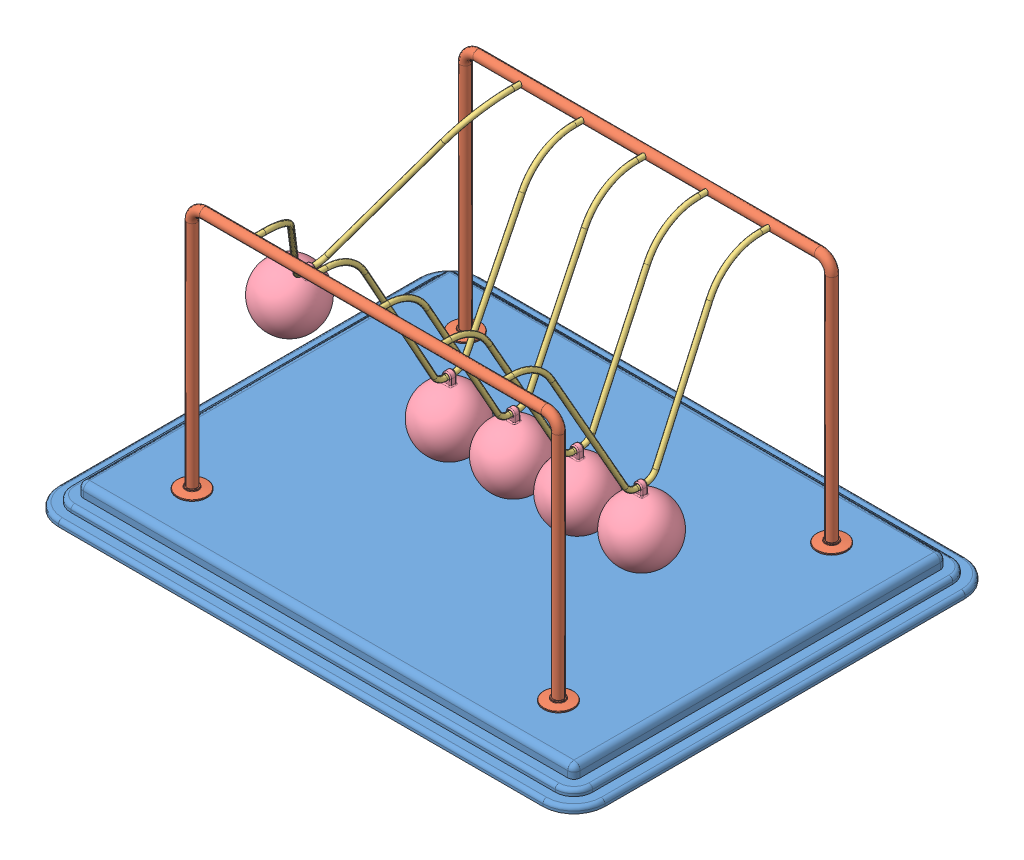
SolidWorks assembly Newtons Cradle NewtonsCradle 0242, configuration Default. Lengths in mm.
Overall size (440 222 340).
13 component instances, 4 part files, 34 mates.
Components (placement in the parent):
- Base NewtonsCradle 0242-1: Base NewtonsCradle 0242 [Default] at (-16.2968 -4.1587 11.425) size (440 20 340)
- frame NewtonsCradle 0242-1: frame NewtonsCradle 0242 [Default] at (-16.2968 144.4547 -98.575) size (319 202 24)
- frame NewtonsCradle 0242-2: frame NewtonsCradle 0242 [Default] at (-16.2968 144.4547 121.425) x (-1 0 0) z (0 0 -1) size (319 202 24)
- Hanging thing NewtonsCradle 0242-1: Hanging thing NewtonsCradle 0242 [Default] at (-157.6326 134.1825 11.425) x (0 0 1) z (-0.859985 0.510319 0) size (220 129 4)
- Hanging thing NewtonsCradle 0242-2: Hanging thing NewtonsCradle 0242 [Default] at (-66.576 122.8418 11.425) x (0 0 1) z (-0.999994 0.003446 0) size (220 129 4)
- Hanging thing NewtonsCradle 0242-3: Hanging thing NewtonsCradle 0242 [Default] at (-15.6923 122.8436 11.425) x (0 0 1) z (-0.999972 -0.007464 0) size (220 129 4)
- Hanging thing NewtonsCradle 0242-4: Hanging thing NewtonsCradle 0242 [Default] at (35.2213 122.8555 11.425) x (0 0 1) z (-0.999824 -0.018742 0) size (220 129 4)
- Hanging thing NewtonsCradle 0242-5: Hanging thing NewtonsCradle 0242 [Default] at (86.0287 122.8747 11.425) x (0 0 1) z (-0.999588 -0.028711 0) size (220 129 4)
- Sphere NewtonsCradle 0242-1: Sphere NewtonsCradle 0242 [Default] at (-195.3962 70.5436 11.425) x (0.859985 -0.510319 0) z (0 0 1) size (50 58.5 50)
- Sphere NewtonsCradle 0242-2: Sphere NewtonsCradle 0242 [Default] at (88.1533 48.9052 11.425) x (0.999588 0.028711 0) z (0 0 1) size (50 58.5 50)
- Sphere NewtonsCradle 0242-3: Sphere NewtonsCradle 0242 [Default] at (-15.14 48.8456 11.425) x (0.999972 0.007464 0) z (0 0 1) size (50 58.5 50)
- Sphere NewtonsCradle 0242-4: Sphere NewtonsCradle 0242 [Default] at (36.6081 48.8685 11.425) x (0.999824 0.018742 0) z (0 0 1) size (50 58.5 50)
- Sphere NewtonsCradle 0242-5: Sphere NewtonsCradle 0242 [Default] at (-66.831 48.8422 11.425) x (0.999994 -0.003446 0) z (0 0 1) size (50 58.5 50)
Mates (geometry in assembly coordinates):
- Coincident1: coincident anti-aligned: plane of Base-1 through (-211.2968 5.8413 156.425) normal (0 1 0); plane of frame-2 through (-175.7968 5.8413 121.425) normal (0 -1 0)
- Coincident2: coincident anti-aligned: plane of Base-1 through (-211.2968 5.8413 156.425) normal (0 1 0); plane of frame-1 through (143.2032 5.8413 -98.575) normal (0 -1 0)
- Concentric1: concentric anti-aligned: cylinder of frame-1 through (-116.2968 203.8413 -94.575) axis (0 0 -1) radius 2; cylinder of frame-2 through (-116.2968 203.8413 117.425) axis (0 0 1) radius 2
- Concentric2: concentric anti-aligned: cylinder of frame-1 through (83.7032 203.8413 -94.575) axis (0 0 -1) radius 2; cylinder of frame-2 through (83.7032 203.8413 117.425) axis (0 0 1) radius 2
- Distance1: distance = 60 mm: plane of frame-1 through (-16.2968 144.4547 -98.575) normal (0 0 1); line of Base-1 through (-211.2968 -12.1587 -158.575) axis (1 0 0)
- Distance2: distance = 60 mm: line of Base-1 through (178.7032 -12.1587 181.425) axis (-1 0 0); plane of frame-2 through (-16.2968 144.4547 121.425) normal (0 0 -1)
- Distance3: distance = 220 mm: plane of frame-2 through (-16.2968 144.4547 121.425) normal (-1 0 0); line of Base-1 through (-236.2968 -12.1587 156.425) axis (0 0 -1)
- Concentric3: concentric anti-aligned: cylinder of frame-1 through (-116.2968 203.8413 -94.575) axis (0 0 -1) radius 2; cylinder of Hanging thing-1 through (-116.2968 203.8413 111.425) axis (0 0 1) radius 2
- Concentric4: concentric anti-aligned: cylinder of frame-1 through (-116.2968 203.8413 -94.575) axis (0 0 -1) radius 2; cylinder of Hanging thing-1 through (-116.2968 203.8413 -98.575) axis (0 0 1) radius 2
- Concentric5: concentric aligned: cylinder of frame-2 through (-66.2968 203.8413 117.425) axis (0 0 1) radius 2; cylinder of Hanging thing-2 through (-66.2968 203.8413 111.425) axis (0 0 1) radius 2
- Concentric6: concentric aligned: cylinder of frame-2 through (-16.2968 203.8413 117.425) axis (0 0 1) radius 2; cylinder of Hanging thing-3 through (-16.2968 203.8413 111.425) axis (0 0 1) radius 2
- Concentric7: concentric aligned: cylinder of frame-2 through (33.7032 203.8413 117.425) axis (0 0 1) radius 2; cylinder of Hanging thing-4 through (33.7032 203.8413 111.425) axis (0 0 1) radius 2
- Concentric8: concentric aligned: cylinder of frame-2 through (83.7032 203.8413 117.425) axis (0 0 1) radius 2; cylinder of Hanging thing-5 through (83.7032 203.8413 111.425) axis (0 0 1) radius 2
- Coincident5: coincident anti-aligned: plane of frame-2 through (83.7032 203.8413 121.425) normal (0 0 -1); plane of Hanging thing-5 through (83.7032 203.8413 121.425) normal (0 0 1)
- Coincident6: coincident anti-aligned: plane of frame-2 through (33.7032 203.8413 121.425) normal (0 0 -1); plane of Hanging thing-4 through (33.7032 203.8413 121.425) normal (0 0 1)
- Coincident7: coincident anti-aligned: plane of frame-2 through (-16.2968 203.8413 121.425) normal (0 0 -1); plane of Hanging thing-3 through (-16.2968 203.8413 121.425) normal (0 0 1)
- Coincident8: coincident anti-aligned: plane of frame-2 through (-66.2968 203.8413 121.425) normal (0 0 -1); plane of Hanging thing-2 through (-66.2968 203.8413 121.425) normal (0 0 1)
- Coincident9: coincident anti-aligned: plane of frame-2 through (-116.2968 203.8413 121.425) normal (0 0 -1); plane of Hanging thing-1 through (-116.2968 203.8413 121.425) normal (0 0 1)
- Concentric9: concentric anti-aligned: cylinder of Hanging thing-1 through (-117.0163 78.8434 7.925) axis (0 0 1) radius 2; cylinder of Sphere-1 through (-117.0163 78.8434 13.925) axis (0 0 -1) radius 2
- Concentric13: concentric anti-aligned: cylinder of Hanging thing-2 through (-66.7276 78.842 7.925) axis (0 0 1) radius 2; cylinder of Sphere-5 through (-66.7276 78.842 13.925) axis (0 0 -1) radius 2
- Concentric15: concentric anti-aligned: cylinder of Hanging thing-3 through (-15.3639 78.8448 7.925) axis (0 0 1) radius 2; cylinder of Sphere-3 through (-15.3639 78.8448 13.925) axis (0 0 -1) radius 2
- Concentric16: concentric anti-aligned: cylinder of Hanging thing-5 through (87.292 78.8928 7.925) axis (0 0 1) radius 2; cylinder of Sphere-2 through (87.292 78.8928 13.925) axis (0 0 -1) radius 2
- Concentric17: concentric anti-aligned: cylinder of Hanging thing-4 through (36.0459 78.8632 7.925) axis (0 0 1) radius 2; cylinder of Sphere-4 through (36.0459 78.8632 13.925) axis (0 0 -1) radius 2
- Parallel1: parallel anti-aligned: plane of Hanging thing-1; plane of Sphere-1
- Coincident22: coincident anti-aligned: plane of Hanging thing-1; plane of Sphere-1
- Coincident12: coincident aligned: plane of Hanging thing-2 through (-66.576 122.8418 11.425) normal (0 0 1); plane of Sphere-5 through (-66.831 48.8422 11.425) normal (0 0 1)
- Coincident10: coincident aligned: plane of Hanging thing-1 through (-116.763 122.8426 11.425) normal (0 0 1); plane of Sphere-1 through (-118.5806 48.8842 11.425) normal (0 0 1)
- Coincident13: coincident anti-aligned: plane of Hanging thing-2 through (-66.576 122.8418 11.425) normal (-0.999994 0.003446 0); plane of Sphere-5 through (-66.831 48.8422 11.425) normal (0.999994 -0.003446 0)
- Coincident14: coincident anti-aligned: plane of Hanging thing-3 through (-15.6923 122.8436 11.425) normal (-0.999972 -0.007464 0); plane of Sphere-3 through (-15.14 48.8456 11.425) normal (0.999972 0.007464 0)
- Coincident15: coincident aligned: plane of Hanging thing-3 through (-15.6923 122.8436 11.425) normal (0 0 1); plane of Sphere-3 through (-15.14 48.8456 11.425) normal (0 0 1)
- Coincident18: coincident aligned: plane of Hanging thing-4 through (35.2213 122.8555 11.425) normal (0 0 1); plane of Sphere-4 through (36.6081 48.8685 11.425) normal (0 0 1)
- Coincident19: coincident anti-aligned: plane of Hanging thing-4 through (35.2213 122.8555 11.425) normal (-0.999824 -0.018742 0); plane of Sphere-4 through (36.6081 48.8685 11.425) normal (0.999824 0.018742 0)
- Coincident20: coincident anti-aligned: plane of Hanging thing-5 through (86.0287 122.8747 11.425) normal (-0.999588 -0.028711 0); plane of Sphere-2 through (88.1533 48.9052 11.425) normal (0.999588 0.028711 0)
- Coincident21: coincident aligned: plane of Hanging thing-5 through (86.0287 122.8747 11.425) normal (0 0 1); plane of Sphere-2 through (88.1533 48.9052 11.425) normal (0 0 1)
